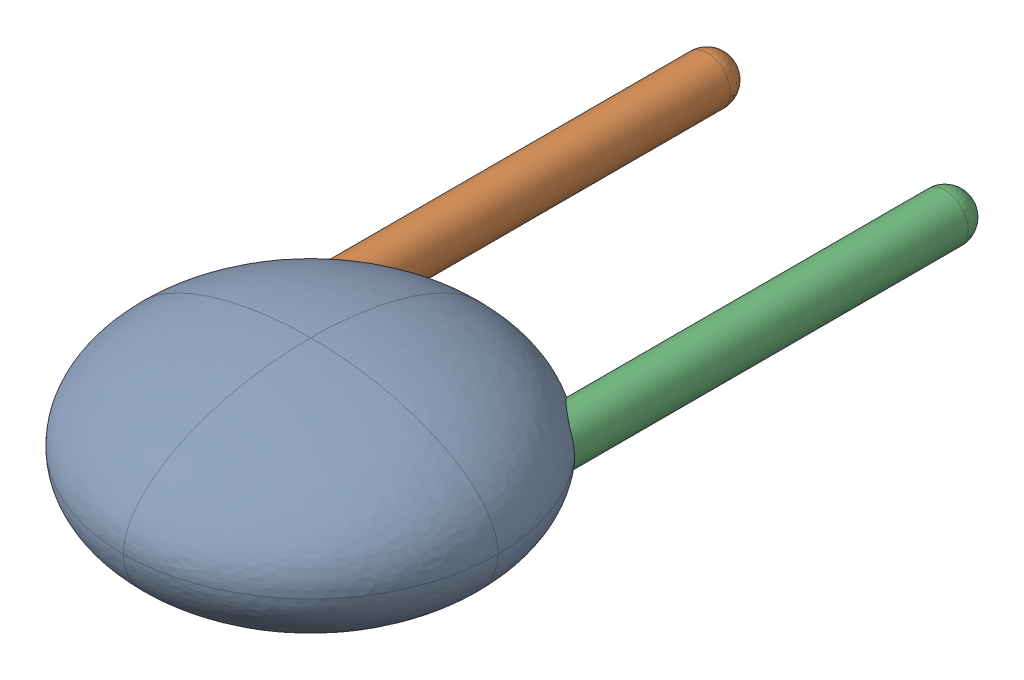
SolidWorks assembly C8, configuration Défaut. Lengths in mm.
Overall size (4 2 7.75).
4 component instances, 3 part files, 0 mates.
Components (placement in the parent):
- Open CASCADE STEP translator 6.8 1.3.1-1: Open CASCADE STEP translator 6.8 1.3.1 [Défaut] at origin size (4 2 7.75)
  - Body_1_2-1: Body_1_2 [Défaut] at (1.27 -1.27 0) x (0 1 0) z (0 0 1) size (2 4 4)
  - Pin_1-1: Pin_1 [Défaut] x (0 -1 0) z (0 0 1) size (0.5 0.5 5.5)
  - Pin_2-1: Pin_2 [Défaut] at (2.54 2.54 0) x (0 -1 0) z (0 0 1) size (0.5 0.5 5.5)
